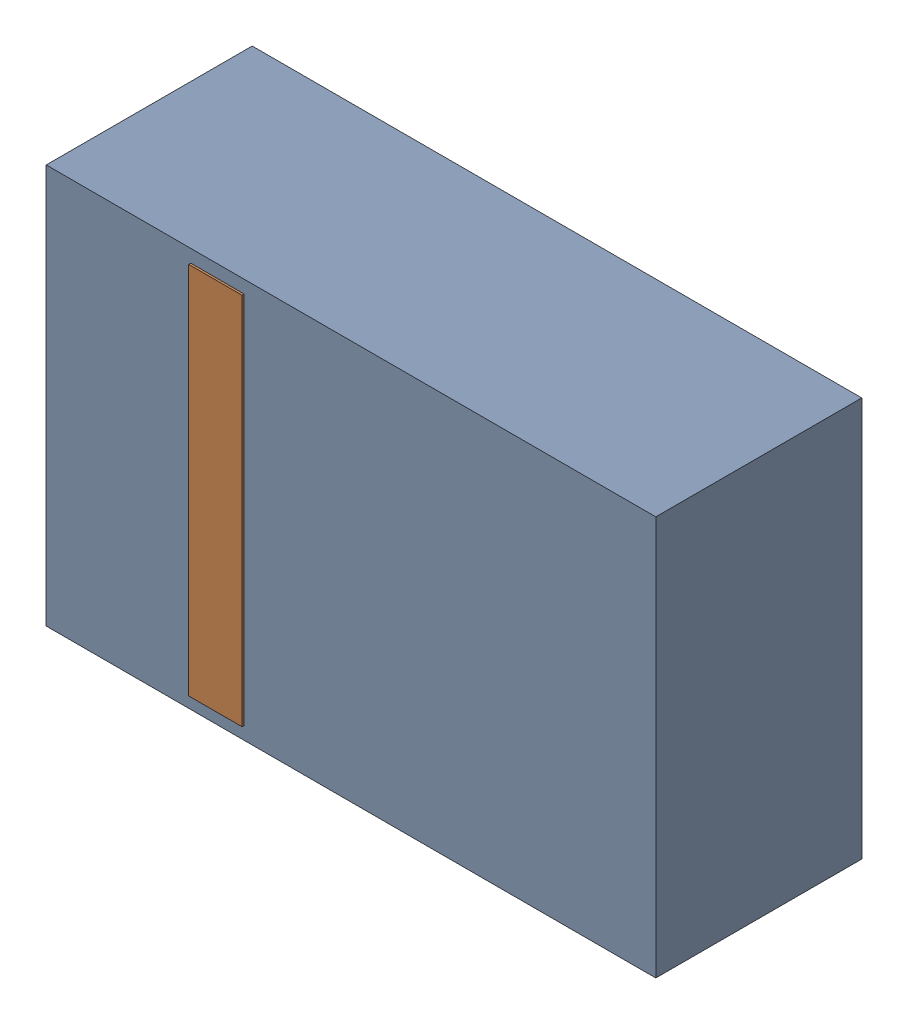
SolidWorks assembly D1, configuration Default. Lengths in mm.
Overall size (2.9 1.9 0.99).
4 component instances, 2 part files, 0 mates.
Components (placement in the parent):
- 905269392-1: 905269392 [Default] at (4.4767 76.5017 0) size (2.9 1.9 0.98)
  - Extruded_5-1: Extruded_5 [Default] at origin size (2.9 1.9 0.98)
- 905269800-1: 905269800 [Default] at (3.8418 76.5017 0.95) size (0.25 1.78 0.04)
  - Extruded_6-1: Extruded_6 [Default] at origin size (0.25 1.78 0.04)
